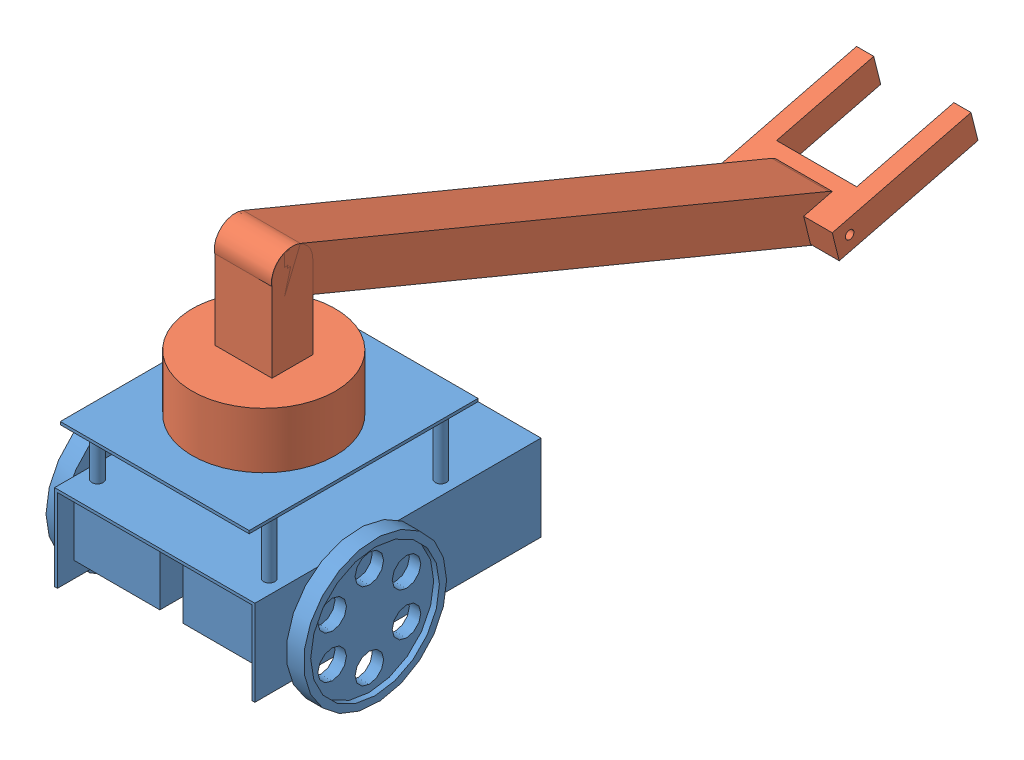
SolidWorks assembly Robot, configuration 預設. Lengths in mm.
Overall size (90 118.9 267.32).
2 component instances, 2 part files, 0 mates.
Components (placement in the parent):
- Robot Body-1: Robot Body [Default] at origin size (90 63 112)
- Robot Arm-1: Robot Arm [預設] at (0.3943 50.4991 -37.7138) x (0 0 1) z (-1 0 0) size (254.61 91.22 50)
